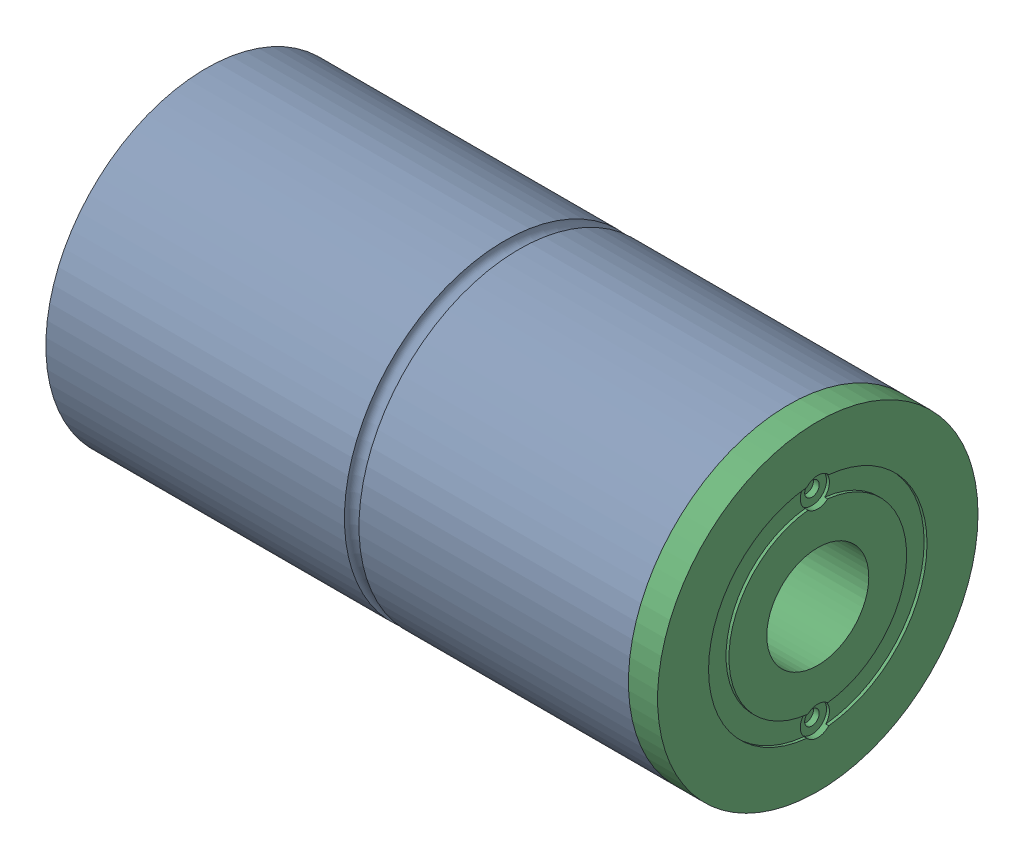
SolidWorks assembly Assem3, configuration Default. Lengths in mm.
Overall size (210 110 110).
3 component instances, 3 part files, 4 mates.
Components (placement in the parent):
- Part1-1: Part1 [Default] at (-168.8827 28.2308 17.1689) size (200 110 110)
- Part3-1: Part3 [Default] at (-158.8827 28.2308 17.1689) x (0 0 -1) z (0 -1 0) size (75 192 75)
- Part2.2-1: Part2.2 [Default] at (41.1173 28.2308 17.1689) x (-1 0 0) z (0 0 1) size (200 110 110)
Mates (geometry in assembly coordinates):
- Coincident3: coincident anti-aligned: circle of Part1-1; plane of Part3-1 through (-158.8827 28.2308 17.1689) normal (-1 0 0)
- Concentric1: concentric anti-aligned: circle of Part1-1; circle of Part3-1
- Coincident4: coincident anti-aligned: circle of Part1-1; plane of Part2.2-1 through (-158.8827 28.2308 17.1689) normal (-1 0 0)
- Coincident5: coincident aligned: circle of Part1-1; circle of Part2.2-1
